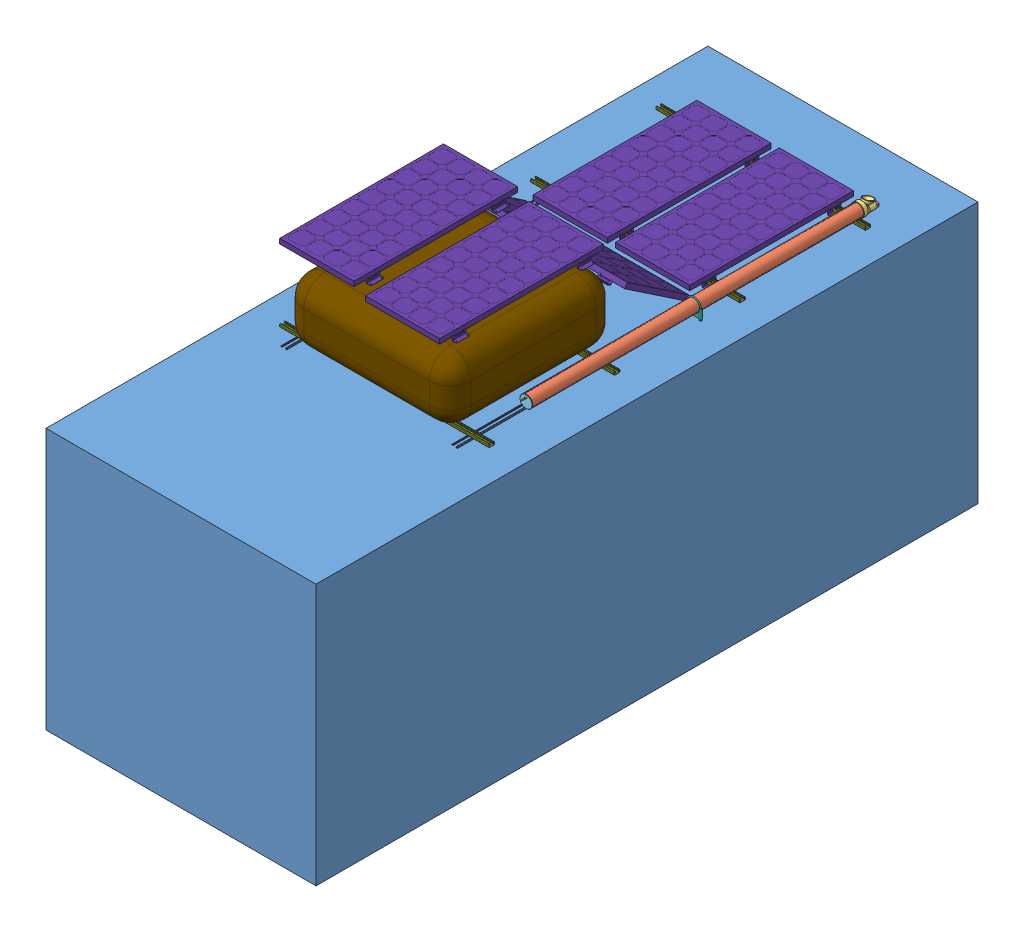
SolidWorks assembly GMC Safari Full Assembly, configuration Default. Lengths in mm.
Overall size (2038.11 2593.29 4815.98).
39 component instances, 20 part files, 13 mates.
Components (placement in the parent):
- AstroVan-2: AstroVan [Default] at origin size (2038.11 1924.47 4826)
- Roof Shower Assembly-1: Roof Shower Assembly [Default] at (672.0007 1980.0087 -740.0532) x (-1 0 0) z (0 0 -1) size (120.45 136.76 2587.07)
  - 3in Pipe-2: 3in Pipe [Default] at origin size (88.9 88.9 2438.4)
  - 3in Pipe Cap with Spigot-1: 3in Pipe Cap with Spigot [Default] at (0 0 1219.2) size (98.78 101.9 117.76)
  - 4211N223_Standard-Wall Plastic Pipe Fitting for Water-1: 4211N223_Standard-Wall Plastic Pipe Fitting for Water [4211N223] at (0 -29.845 1310.64) x (0 0 -1) z (1 0 0) size (40.99 36.57 33.53)
  - 3in Cap-1: 3in Cap [Default] at (0 0 -1219.2) x (-1 0 0) z (0 0 -1) size (88.9 88.9 16.51)
  - 3042T37_Clamping U-Bolt-1: 3042T37_Clamping U-Bolt [3042T37] at (0 -2.2058 -0.7136) x (-1 0 0) z (0 0 1) size (120.45 136.76 18.85)
  - CKAuto TR416 Metal Valve Stem-2: CKAuto TR416 Metal Valve Stem [Default] at (0 24.5999 -1212.1896) x (1 0 0) z (0 1 0) size (18.52 40.06 18.52)
    - CKAuto TR416 Metal Valve Base-2: CKAuto TR416 Metal Valve Base [Default] at origin size (18.52 40.06 18.52)
    - Part12^CKAuto TR416 Metal Valve Stem-1: Part12^CKAuto TR416 Metal Valve Stem [Default] x (0 0 -1) z (1 0 0) size (17.78 7.25 17.78) (virtual)
  - 4880K542_Standard-Wall PVC Pipe Fitting for Water-1: 4880K542_Standard-Wall PVC Pipe Fitting for Water [4880K542] at (0 16.6115 1238.9262) x (-0.855307 0.396317 -0.333741) z (0 -0.644136 -0.764911) size (29.77 29.77 27)
- Roof Rack Assembly-1: Roof Rack Assembly [Default] at (0 1892.9986 -569.7276) size (1524 88.07 3048)
  - Roof Rack Strut-1: Roof Rack Strut [Default] at (0 -1893.0006 566.2194) size (41.28 67.43 3048)
    - 3310T8_Strut Channel-1: 3310T8_Strut Channel [3310T8] at (-622.3 1893.0006 957.7806) x (0 -1 0) z (0 0 1) size (20.64 41.27 3048)
    - Center Spacer V1-1: Center Spacer V1 [Default] at (-622.3 1880.3006 -584.4756) size (31.75 16.33 76.2)
    - Front Center Spacer V1-1: Front Center Spacer V1 [Default] at (-622.3 1878.7131 126.7244) size (31.75 18.31 76.2)
    - Front Spacer V1-1: Front Spacer V1 [Default] at (-622.3 1854.9006 772.8369) size (31.75 46.79 76.2)
    - Rear Center Spacer V1-1: Rear Center Spacer V1 [Default] at (-622.3 1881.8881 -1309.9631) size (31.75 14.47 76.2)
    - Rear Spacer V1-1: Rear Spacer V1 [Default] at (-622.3 1858.0756 -1956.0756) size (31.75 40.44 76.2)
  - Roof Rack Strut-3: Roof Rack Strut [Default] at (1244.6 -1893.0006 566.2194) size (41.28 67.43 3048)
    - 3310T8_Strut Channel-1: 3310T8_Strut Channel [3310T8] at (-622.3 1893.0006 957.7806) x (0 -1 0) z (0 0 1) size (20.64 41.27 3048)
    - Center Spacer V1-1: Center Spacer V1 [Default] at (-622.3 1880.3006 -584.4756) size (31.75 16.33 76.2)
    - Front Center Spacer V1-1: Front Center Spacer V1 [Default] at (-622.3 1878.7131 126.7244) size (31.75 18.31 76.2)
    - Front Spacer V1-1: Front Spacer V1 [Default] at (-622.3 1854.9006 772.8369) size (31.75 46.79 76.2)
    - Rear Center Spacer V1-1: Rear Center Spacer V1 [Default] at (-622.3 1881.8881 -1309.9631) size (31.75 14.47 76.2)
    - Rear Spacer V1-1: Rear Spacer V1 [Default] at (-622.3 1858.0756 -1956.0756) size (31.75 40.44 76.2)
  - 3310T49_Strut Channel-1: 3310T49_Strut Channel [3310T49] at (762 20.6375 -1349.6443) x (0 -1 0) z (1 0 0) size (20.64 41.27 1524)
  - 3310T49_Strut Channel-2: 3310T49_Strut Channel [3310T49] at (762 20.6375 -435.2443) x (0 -1 0) z (1 0 0) size (20.64 41.27 1524)
  - 3310T49_Strut Channel-3: 3310T49_Strut Channel [3310T49] at (762 20.6375 479.1557) x (0 -1 0) z (1 0 0) size (20.64 41.27 1524)
  - 3310T49_Strut Channel-4: 3310T49_Strut Channel [3310T49] at (762 20.6375 1393.5557) x (0 -1 0) z (1 0 0) size (20.64 41.27 1524)
- SOLAR PANEL ASSY-1: SOLAR PANEL ASSY [Default] at (-347.1755 1934.2736 -1455.4223) size (609.45 57.79 1193.8)
- SOLAR PANEL ASSY-2: SOLAR PANEL ASSY [Default] at (253.1869 1934.2736 -1455.4223) size (609.45 57.79 1193.8)
- Cargo Box-1: Cargo Box [Default] at (-12.5362 1930.583 351.0869) size (1219.2 457.2 1219.2)
- SOLAR PANEL ASSY-3: SOLAR PANEL ASSY [Default] at (-20.7855 2085.5422 -556.5816) x (0 -0.559198 -0.829034) z (1 0 0) size (609.45 57.79 1193.8)
- SOLAR PANEL ASSY-4: SOLAR PANEL ASSY [Default] at (187.4941 2443.0303 301.5496) size (609.45 57.79 1193.8)
- SOLAR PANEL ASSY-5: SOLAR PANEL ASSY [Default] at (-388.7731 2541.6943 350.5119) size (609.45 57.79 1193.8)
- Roof Electrical Connection-1: Roof Electrical Connection [Default] at origin size (63.99 101.76 132.11)
  - Goosneck Electrical Inlet V1-1: Goosneck Electrical Inlet V1 [Default] at origin size (63.5 101.07 131.86)
  - Roof Electrical Connection Nut-1: Roof Electrical Connection Nut [Default] at (0 -2.54 0) x (-1 0 0) z (0 -1 0) size (63.99 63.99 14.73)
Mates (geometry in assembly coordinates):
- Coincident1: coordinate: point of AstroVan-2
- Coincident13: coincident aligned: plane of Roof Rack Assembly-1 through (0 1892.9986 -569.7276) normal (1 0 0)
- Coincident15: coincident: face of ?; unknown of Roof Rack Assembly-1/Roof Rack Strut-1/Center Spacer V1-1
- Parallel4: parallel anti-aligned: plane of Roof Rack Assembly-1/Roof Rack Strut-1/3310T8_Strut Channel-1 through (-605.1232 1892.9986 -2093.7276) normal (0 -1 0)
- Coincident17: coincident anti-aligned: plane of Roof Rack Assembly-1/3310T49_Strut Channel-1 through (-762 1934.2736 -1934.9611) normal (0 1 0); plane of SOLAR PANEL ASSY-2 through (253.1869 1934.2736 -1455.4223) normal (0 -1 0)
- Distance3: distance = 569.7276 mm aligned: plane of Roof Rack Assembly-1 through (0 1892.9986 -569.7276) normal (0 0 1)
- Coincident19: coincident anti-aligned: plane of Roof Rack Assembly-1/3310T49_Strut Channel-1 through (-762 1934.2736 -1934.9611) normal (0 1 0); plane of SOLAR PANEL ASSY-1 through (-347.1755 1934.2736 -1455.4223) normal (0 -1 0)
- Coincident20: coincident anti-aligned: plane of Roof Shower Assembly-1/3042T37_Clamping U-Bolt-1 through (722.8007 1915.6681 -739.3396) normal (0 -1 0); plane of Roof Rack Assembly-1/3310T49_Strut Channel-2 through (-762 1915.6681 -987.7951) normal (0 1 0)
- Coincident21: coincident aligned: plane of SOLAR PANEL ASSY-1 through (-617.6855 1969.8336 -858.5223) normal (0 0 1); plane of SOLAR PANEL ASSY-2 through (-17.3231 1969.8336 -858.5223) normal (0 0 1)
- Coincident23: coincident: plane of Roof Rack Assembly-1/3310T49_Strut Channel-2 through (-762 1934.2736 -989.3826) normal (0 1 0); line of SOLAR PANEL ASSY-3 through (576.1145 1934.2736 -780.8436) axis (-1 0 0)
- Coincident24: coincident aligned: plane of SOLAR PANEL ASSY-1 through (-617.6855 1969.8336 -2052.3223) normal (-1 0 0); plane of SOLAR PANEL ASSY-3 through (-617.6855 2266.2912 -352.2046) normal (-1 0 0)
- Parallel6: parallel anti-aligned: plane of Roof Shower Assembly-1 through (672.0007 1980.0087 -740.0532) normal (-1 0 0)
- Parallel8: parallel anti-aligned: plane of Roof Electrical Connection-1/Goosneck Electrical Inlet V1-1 through (0 -2.54 0) normal (0 -1 0)
